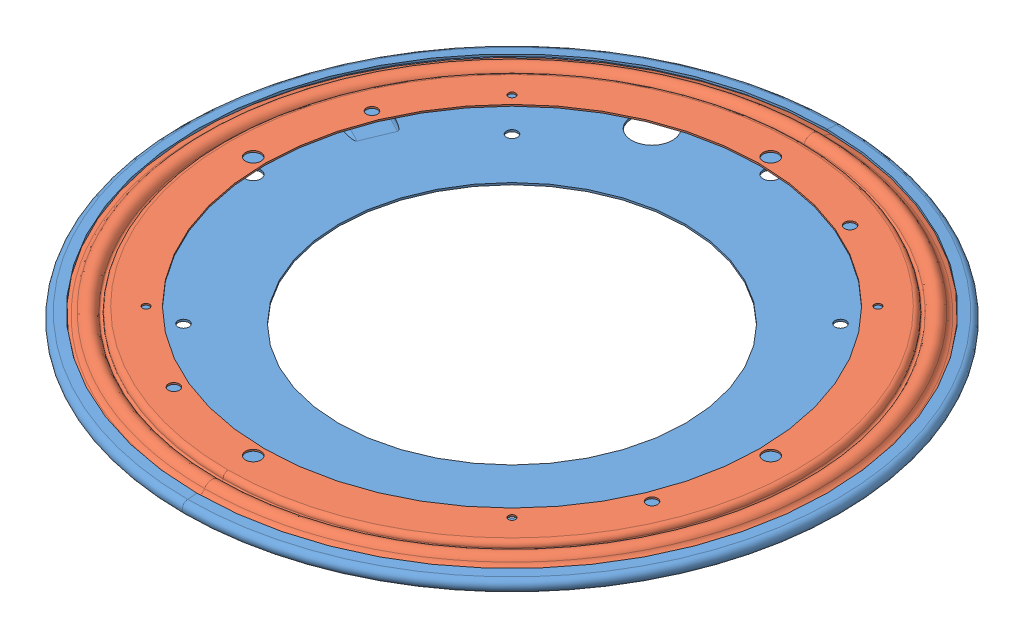
SolidWorks assembly GE-20150, configuration Default. Lengths in mm.
Overall size (306.54 10.35 306.54).
139 component instances, 3 part files, 0 mates.
Components (placement in the parent):
- triangle-mfg-lazy-susan-bearing-12c.STEP-1: triangle-mfg-lazy-susan-bearing-12c.STEP [Default] at origin size (306.54 10.35 306.54)
  - MSTR 12 Inch Locking Race_1865a.STEP-1: MSTR 12 Inch Locking Race_1865a.STEP [Default] at origin size (306.54 5.95 306.54)
  - MSTR 12 Inch Plain Race_1866.STEP-1: MSTR 12 Inch Plain Race_1866.STEP [Default] at (0 2.1844 0) x (-1 0 0) z (0 0 -1) size (297.66 5.77 297.66)
  - MSTR Suzie Ball_Balls12.STEP-1: MSTR Suzie Ball_Balls12.STEP [Default] at (139.5019 4.0386 0) x (-0.848035 -0.486854 -0.209308) z (-0.404097 0.338557 0.849756) size (6.35 6.35 6.35)
  - MSTR Suzie Ball_Balls12.STEP-2: MSTR Suzie Ball_Balls12.STEP [Default] at (139.353 4.0386 6.4427) x (-0.837464 -0.486854 -0.24825) z (-0.442911 0.338557 0.830186) size (6.35 6.35 6.35)
  - MSTR Suzie Ball_Balls12.STEP-3: MSTR Suzie Ball_Balls12.STEP [Default] at (138.9068 4.0386 12.8716) x (-0.825105 -0.486854 -0.286662) z (-0.480779 0.338557 0.808845) size (6.35 6.35 6.35)
  - MSTR Suzie Ball_Balls12.STEP-4: MSTR Suzie Ball_Balls12.STEP [Default] at (138.1641 4.0386 19.2731) x (-0.810985 -0.486854 -0.324463) z (-0.517621 0.338557 0.785778) size (6.35 6.35 6.35)
  - MSTR Suzie Ball_Balls12.STEP-5: MSTR Suzie Ball_Balls12.STEP [Default] at (137.1266 4.0386 25.6334) x (-0.795135 -0.486854 -0.361571) z (-0.553359 0.338557 0.761034) size (6.35 6.35 6.35)
  - MSTR Suzie Ball_Balls12.STEP-6: MSTR Suzie Ball_Balls12.STEP [Default] at (135.7964 4.0386 31.939) x (-0.777588 -0.486854 -0.397907) z (-0.587916 0.338557 0.734666) size (6.35 6.35 6.35)
  - MSTR Suzie Ball_Balls12.STEP-7: MSTR Suzie Ball_Balls12.STEP [Default] at (134.1765 4.0386 38.1765) x (-0.758382 -0.486854 -0.433394) z (-0.621218 0.338557 0.70673) size (6.35 6.35 6.35)
  - MSTR Suzie Ball_Balls12.STEP-8: MSTR Suzie Ball_Balls12.STEP [Default] at (132.2702 4.0386 44.3325) x (-0.737557 -0.486854 -0.467956) z (-0.653194 0.338557 0.677286) size (6.35 6.35 6.35)
  - MSTR Suzie Ball_Balls12.STEP-9: MSTR Suzie Ball_Balls12.STEP [Default] at (130.0816 4.0386 50.3939) x (-0.715158 -0.486854 -0.50152) z (-0.683777 0.338557 0.646397) size (6.35 6.35 6.35)
  - MSTR Suzie Ball_Balls12.STEP-10: MSTR Suzie Ball_Balls12.STEP [Default] at (127.6155 4.0386 56.3477) x (-0.691233 -0.486854 -0.534013) z (-0.7129 0.338557 0.614128) size (6.35 6.35 6.35)
  - MSTR Suzie Ball_Balls12.STEP-11: MSTR Suzie Ball_Balls12.STEP [Default] at (124.877 4.0386 62.1813) x (-0.665833 -0.486854 -0.565367) z (-0.740502 0.338557 0.580548) size (6.35 6.35 6.35)
  - MSTR Suzie Ball_Balls12.STEP-12: MSTR Suzie Ball_Balls12.STEP [Default] at (121.872 4.0386 67.8822) x (-0.639012 -0.486854 -0.595514) z (-0.766523 0.338557 0.54573) size (6.35 6.35 6.35)
  - MSTR Suzie Ball_Balls12.STEP-13: MSTR Suzie Ball_Balls12.STEP [Default] at (118.6069 4.0386 73.4383) x (-0.610827 -0.486854 -0.624391) z (-0.790909 0.338557 0.509747) size (6.35 6.35 6.35)
  - MSTR Suzie Ball_Balls12.STEP-14: MSTR Suzie Ball_Balls12.STEP [Default] at (115.0887 4.0386 78.8376) x (-0.581339 -0.486854 -0.651934) z (-0.813607 0.338557 0.472676) size (6.35 6.35 6.35)
  - MSTR Suzie Ball_Balls12.STEP-15: MSTR Suzie Ball_Balls12.STEP [Default] at (111.3249 4.0386 84.0687) x (-0.55061 -0.486854 -0.678087) z (-0.834569 0.338557 0.434597) size (6.35 6.35 6.35)
  - MSTR Suzie Ball_Balls12.STEP-16: MSTR Suzie Ball_Balls12.STEP [Default] at (107.3235 4.0386 89.1203) x (-0.518706 -0.486854 -0.702793) z (-0.853749 0.338557 0.39559) size (6.35 6.35 6.35)
  - MSTR Suzie Ball_Balls12.STEP-17: MSTR Suzie Ball_Balls12.STEP [Default] at (103.0931 4.0386 93.9818) x (-0.485695 -0.486854 -0.725998) z (-0.871108 0.338557 0.355738) size (6.35 6.35 6.35)
  - MSTR Suzie Ball_Balls12.STEP-18: MSTR Suzie Ball_Balls12.STEP [Default] at (98.6427 4.0386 98.6427) x (-0.451648 -0.486854 -0.747655) z (-0.886608 0.338557 0.315128) size (6.35 6.35 6.35)
  - MSTR Suzie Ball_Balls12.STEP-19: MSTR Suzie Ball_Balls12.STEP [Default] at (93.9818 4.0386 103.0931) x (-0.416637 -0.486854 -0.767716) z (-0.900216 0.338557 0.273845) size (6.35 6.35 6.35)
  - MSTR Suzie Ball_Balls12.STEP-20: MSTR Suzie Ball_Balls12.STEP [Default] at (89.1203 4.0386 107.3235) x (-0.380736 -0.486854 -0.786138) z (-0.911902 0.338557 0.231978) size (6.35 6.35 6.35)
  - MSTR Suzie Ball_Balls12.STEP-21: MSTR Suzie Ball_Balls12.STEP [Default] at (84.0687 4.0386 111.3249) x (-0.344024 -0.486854 -0.802883) z (-0.921643 0.338557 0.189616) size (6.35 6.35 6.35)
  - MSTR Suzie Ball_Balls12.STEP-22: MSTR Suzie Ball_Balls12.STEP [Default] at (78.8376 4.0386 115.0887) x (-0.306577 -0.486854 -0.817915) z (-0.929416 0.338557 0.146849) size (6.35 6.35 6.35)
  - MSTR Suzie Ball_Balls12.STEP-23: MSTR Suzie Ball_Balls12.STEP [Default] at (73.4383 4.0386 118.6069) x (-0.268475 -0.486854 -0.831201) z (-0.935207 0.338557 0.103768) size (6.35 6.35 6.35)
  - MSTR Suzie Ball_Balls12.STEP-24: MSTR Suzie Ball_Balls12.STEP [Default] at (67.8822 4.0386 121.872) x (-0.229801 -0.486854 -0.842713) z (-0.939001 0.338557 0.060466) size (6.35 6.35 6.35)
  - MSTR Suzie Ball_Balls12.STEP-25: MSTR Suzie Ball_Balls12.STEP [Default] at (62.1813 4.0386 124.877) x (-0.190637 -0.486854 -0.852427) z (-0.940792 0.338557 0.017036) size (6.35 6.35 6.35)
  - MSTR Suzie Ball_Balls12.STEP-26: MSTR Suzie Ball_Balls12.STEP [Default] at (56.3477 4.0386 127.6155) x (-0.151065 -0.486854 -0.860321) z (-0.940575 0.338557 -0.026432) size (6.35 6.35 6.35)
  - MSTR Suzie Ball_Balls12.STEP-27: MSTR Suzie Ball_Balls12.STEP [Default] at (50.3939 4.0386 130.0816) x (-0.111171 -0.486854 -0.86638) z (-0.93835 0.338557 -0.069842) size (6.35 6.35 6.35)
  - MSTR Suzie Ball_Balls12.STEP-28: MSTR Suzie Ball_Balls12.STEP [Default] at (44.3325 4.0386 132.2702) x (-0.07104 -0.486854 -0.87059) z (-0.934124 0.338557 -0.113104) size (6.35 6.35 6.35)
  - MSTR Suzie Ball_Balls12.STEP-29: MSTR Suzie Ball_Balls12.STEP [Default] at (38.1765 4.0386 134.1765) x (-0.030758 -0.486854 -0.872942) z (-0.927903 0.338557 -0.156124) size (6.35 6.35 6.35)
  - MSTR Suzie Ball_Balls12.STEP-30: MSTR Suzie Ball_Balls12.STEP [Default] at (31.939 4.0386 135.7964) x (0.009591 -0.486854 -0.873431) z (-0.919703 0.338557 -0.198812) size (6.35 6.35 6.35)
  - MSTR Suzie Ball_Balls12.STEP-31: MSTR Suzie Ball_Balls12.STEP [Default] at (25.6334 4.0386 137.1266) x (0.049918 -0.486854 -0.872056) z (-0.90954 0.338557 -0.241075) size (6.35 6.35 6.35)
  - MSTR Suzie Ball_Balls12.STEP-32: MSTR Suzie Ball_Balls12.STEP [Default] at (19.2731 4.0386 138.1641) x (0.09014 -0.486854 -0.86882) z (-0.897435 0.338557 -0.282823) size (6.35 6.35 6.35)
  - MSTR Suzie Ball_Balls12.STEP-33: MSTR Suzie Ball_Balls12.STEP [Default] at (12.8716 4.0386 138.9068) x (0.130169 -0.486854 -0.86373) z (-0.883416 0.338557 -0.323968) size (6.35 6.35 6.35)
  - MSTR Suzie Ball_Balls12.STEP-34: MSTR Suzie Ball_Balls12.STEP [Default] at (6.4427 4.0386 139.353) x (0.16992 -0.486854 -0.856797) z (-0.867512 0.338557 -0.364421) size (6.35 6.35 6.35)
  - MSTR Suzie Ball_Balls12.STEP-35: MSTR Suzie Ball_Balls12.STEP [Default] at (0 4.0386 139.5019) x (0.209308 -0.486854 -0.848035) z (-0.849756 0.338557 -0.404097) size (6.35 6.35 6.35)
  - MSTR Suzie Ball_Balls12.STEP-36: MSTR Suzie Ball_Balls12.STEP [Default] at (-6.4427 4.0386 139.353) x (0.24825 -0.486854 -0.837464) z (-0.830186 0.338557 -0.442911) size (6.35 6.35 6.35)
  - MSTR Suzie Ball_Balls12.STEP-37: MSTR Suzie Ball_Balls12.STEP [Default] at (-12.8716 4.0386 138.9068) x (0.286662 -0.486854 -0.825105) z (-0.808845 0.338557 -0.480779) size (6.35 6.35 6.35)
  - MSTR Suzie Ball_Balls12.STEP-38: MSTR Suzie Ball_Balls12.STEP [Default] at (-19.2731 4.0386 138.1641) x (0.324463 -0.486854 -0.810985) z (-0.785778 0.338557 -0.517621) size (6.35 6.35 6.35)
  - MSTR Suzie Ball_Balls12.STEP-39: MSTR Suzie Ball_Balls12.STEP [Default] at (-25.6334 4.0386 137.1266) x (0.361571 -0.486854 -0.795135) z (-0.761034 0.338557 -0.553359) size (6.35 6.35 6.35)
  - MSTR Suzie Ball_Balls12.STEP-40: MSTR Suzie Ball_Balls12.STEP [Default] at (-31.939 4.0386 135.7964) x (0.397907 -0.486854 -0.777588) z (-0.734666 0.338557 -0.587916) size (6.35 6.35 6.35)
  - MSTR Suzie Ball_Balls12.STEP-41: MSTR Suzie Ball_Balls12.STEP [Default] at (-38.1765 4.0386 134.1765) x (0.433394 -0.486854 -0.758382) z (-0.70673 0.338557 -0.621218) size (6.35 6.35 6.35)
  - MSTR Suzie Ball_Balls12.STEP-42: MSTR Suzie Ball_Balls12.STEP [Default] at (-44.3325 4.0386 132.2702) x (0.467956 -0.486854 -0.737557) z (-0.677286 0.338557 -0.653194) size (6.35 6.35 6.35)
  - MSTR Suzie Ball_Balls12.STEP-43: MSTR Suzie Ball_Balls12.STEP [Default] at (-50.3939 4.0386 130.0816) x (0.50152 -0.486854 -0.715158) z (-0.646397 0.338557 -0.683777) size (6.35 6.35 6.35)
  - MSTR Suzie Ball_Balls12.STEP-44: MSTR Suzie Ball_Balls12.STEP [Default] at (-56.3477 4.0386 127.6155) x (0.534013 -0.486854 -0.691233) z (-0.614128 0.338557 -0.7129) size (6.35 6.35 6.35)
  - MSTR Suzie Ball_Balls12.STEP-45: MSTR Suzie Ball_Balls12.STEP [Default] at (-62.1813 4.0386 124.877) x (0.565367 -0.486854 -0.665833) z (-0.580548 0.338557 -0.740502) size (6.35 6.35 6.35)
  - MSTR Suzie Ball_Balls12.STEP-46: MSTR Suzie Ball_Balls12.STEP [Default] at (-67.8822 4.0386 121.872) x (0.595514 -0.486854 -0.639012) z (-0.54573 0.338557 -0.766523) size (6.35 6.35 6.35)
  - MSTR Suzie Ball_Balls12.STEP-47: MSTR Suzie Ball_Balls12.STEP [Default] at (-73.4383 4.0386 118.6069) x (0.624391 -0.486854 -0.610827) z (-0.509747 0.338557 -0.790909) size (6.35 6.35 6.35)
  - MSTR Suzie Ball_Balls12.STEP-48: MSTR Suzie Ball_Balls12.STEP [Default] at (-78.8376 4.0386 115.0887) x (0.651934 -0.486854 -0.581339) z (-0.472676 0.338557 -0.813607) size (6.35 6.35 6.35)
  - MSTR Suzie Ball_Balls12.STEP-49: MSTR Suzie Ball_Balls12.STEP [Default] at (-84.0687 4.0386 111.3249) x (0.678087 -0.486854 -0.55061) z (-0.434597 0.338557 -0.834569) size (6.35 6.35 6.35)
  - MSTR Suzie Ball_Balls12.STEP-50: MSTR Suzie Ball_Balls12.STEP [Default] at (-89.1203 4.0386 107.3235) x (0.702793 -0.486854 -0.518706) z (-0.39559 0.338557 -0.853749) size (6.35 6.35 6.35)
  - MSTR Suzie Ball_Balls12.STEP-51: MSTR Suzie Ball_Balls12.STEP [Default] at (-93.9818 4.0386 103.0931) x (0.725998 -0.486854 -0.485695) z (-0.355738 0.338557 -0.871108) size (6.35 6.35 6.35)
  - MSTR Suzie Ball_Balls12.STEP-52: MSTR Suzie Ball_Balls12.STEP [Default] at (-98.6427 4.0386 98.6427) x (0.747655 -0.486854 -0.451648) z (-0.315128 0.338557 -0.886608) size (6.35 6.35 6.35)
  - MSTR Suzie Ball_Balls12.STEP-53: MSTR Suzie Ball_Balls12.STEP [Default] at (-103.0931 4.0386 93.9818) x (0.767716 -0.486854 -0.416637) z (-0.273845 0.338557 -0.900216) size (6.35 6.35 6.35)
  - MSTR Suzie Ball_Balls12.STEP-54: MSTR Suzie Ball_Balls12.STEP [Default] at (-107.3235 4.0386 89.1203) x (0.786138 -0.486854 -0.380736) z (-0.231978 0.338557 -0.911902) size (6.35 6.35 6.35)
  - MSTR Suzie Ball_Balls12.STEP-55: MSTR Suzie Ball_Balls12.STEP [Default] at (-111.3249 4.0386 84.0687) x (0.802883 -0.486854 -0.344024) z (-0.189616 0.338557 -0.921643) size (6.35 6.35 6.35)
  - MSTR Suzie Ball_Balls12.STEP-56: MSTR Suzie Ball_Balls12.STEP [Default] at (-115.0887 4.0386 78.8376) x (0.817915 -0.486854 -0.306577) z (-0.146849 0.338557 -0.929416) size (6.35 6.35 6.35)
  - MSTR Suzie Ball_Balls12.STEP-57: MSTR Suzie Ball_Balls12.STEP [Default] at (-118.6069 4.0386 73.4383) x (0.831201 -0.486854 -0.268475) z (-0.103768 0.338557 -0.935207) size (6.35 6.35 6.35)
  - MSTR Suzie Ball_Balls12.STEP-58: MSTR Suzie Ball_Balls12.STEP [Default] at (-121.872 4.0386 67.8822) x (0.842713 -0.486854 -0.229801) z (-0.060466 0.338557 -0.939001) size (6.35 6.35 6.35)
  - MSTR Suzie Ball_Balls12.STEP-59: MSTR Suzie Ball_Balls12.STEP [Default] at (-124.877 4.0386 62.1813) x (0.852427 -0.486854 -0.190637) z (-0.017036 0.338557 -0.940792) size (6.35 6.35 6.35)
  - MSTR Suzie Ball_Balls12.STEP-60: MSTR Suzie Ball_Balls12.STEP [Default] at (-127.6155 4.0386 56.3477) x (0.860321 -0.486854 -0.151065) z (0.026432 0.338557 -0.940575) size (6.35 6.35 6.35)
  - MSTR Suzie Ball_Balls12.STEP-61: MSTR Suzie Ball_Balls12.STEP [Default] at (-130.0816 4.0386 50.3939) x (0.86638 -0.486854 -0.111171) z (0.069842 0.338557 -0.93835) size (6.35 6.35 6.35)
  - MSTR Suzie Ball_Balls12.STEP-62: MSTR Suzie Ball_Balls12.STEP [Default] at (-132.2702 4.0386 44.3325) x (0.87059 -0.486854 -0.07104) z (0.113104 0.338557 -0.934124) size (6.35 6.35 6.35)
  - MSTR Suzie Ball_Balls12.STEP-63: MSTR Suzie Ball_Balls12.STEP [Default] at (-134.1765 4.0386 38.1765) x (0.872942 -0.486854 -0.030758) z (0.156124 0.338557 -0.927903) size (6.35 6.35 6.35)
  - MSTR Suzie Ball_Balls12.STEP-64: MSTR Suzie Ball_Balls12.STEP [Default] at (-135.7964 4.0386 31.939) x (0.873431 -0.486854 0.009591) z (0.198812 0.338557 -0.919703) size (6.35 6.35 6.35)
  - MSTR Suzie Ball_Balls12.STEP-65: MSTR Suzie Ball_Balls12.STEP [Default] at (-137.1266 4.0386 25.6334) x (0.872056 -0.486854 0.049918) z (0.241075 0.338557 -0.90954) size (6.35 6.35 6.35)
  - MSTR Suzie Ball_Balls12.STEP-66: MSTR Suzie Ball_Balls12.STEP [Default] at (-138.1641 4.0386 19.2731) x (0.86882 -0.486854 0.09014) z (0.282823 0.338557 -0.897435) size (6.35 6.35 6.35)
  - MSTR Suzie Ball_Balls12.STEP-67: MSTR Suzie Ball_Balls12.STEP [Default] at (-138.9068 4.0386 12.8716) x (0.86373 -0.486854 0.130169) z (0.323968 0.338557 -0.883416) size (6.35 6.35 6.35)
  - MSTR Suzie Ball_Balls12.STEP-68: MSTR Suzie Ball_Balls12.STEP [Default] at (-139.353 4.0386 6.4427) x (0.856797 -0.486854 0.16992) z (0.364421 0.338557 -0.867512) size (6.35 6.35 6.35)
  - MSTR Suzie Ball_Balls12.STEP-69: MSTR Suzie Ball_Balls12.STEP [Default] at (-139.5019 4.0386 0) x (0.848035 -0.486854 0.209308) z (0.404097 0.338557 -0.849756) size (6.35 6.35 6.35)
  - MSTR Suzie Ball_Balls12.STEP-70: MSTR Suzie Ball_Balls12.STEP [Default] at (-139.353 4.0386 -6.4427) x (0.837464 -0.486854 0.24825) z (0.442911 0.338557 -0.830186) size (6.35 6.35 6.35)
  - MSTR Suzie Ball_Balls12.STEP-71: MSTR Suzie Ball_Balls12.STEP [Default] at (-138.9068 4.0386 -12.8716) x (0.825105 -0.486854 0.286662) z (0.480779 0.338557 -0.808845) size (6.35 6.35 6.35)
  - MSTR Suzie Ball_Balls12.STEP-72: MSTR Suzie Ball_Balls12.STEP [Default] at (-138.1641 4.0386 -19.2731) x (0.810985 -0.486854 0.324463) z (0.517621 0.338557 -0.785778) size (6.35 6.35 6.35)
  - MSTR Suzie Ball_Balls12.STEP-73: MSTR Suzie Ball_Balls12.STEP [Default] at (-137.1266 4.0386 -25.6334) x (0.795135 -0.486854 0.361571) z (0.553359 0.338557 -0.761034) size (6.35 6.35 6.35)
  - MSTR Suzie Ball_Balls12.STEP-74: MSTR Suzie Ball_Balls12.STEP [Default] at (-135.7964 4.0386 -31.939) x (0.777588 -0.486854 0.397907) z (0.587916 0.338557 -0.734666) size (6.35 6.35 6.35)
  - MSTR Suzie Ball_Balls12.STEP-75: MSTR Suzie Ball_Balls12.STEP [Default] at (-134.1765 4.0386 -38.1765) x (0.758382 -0.486854 0.433394) z (0.621218 0.338557 -0.70673) size (6.35 6.35 6.35)
  - MSTR Suzie Ball_Balls12.STEP-76: MSTR Suzie Ball_Balls12.STEP [Default] at (-132.2702 4.0386 -44.3325) x (0.737557 -0.486854 0.467956) z (0.653194 0.338557 -0.677286) size (6.35 6.35 6.35)
  - MSTR Suzie Ball_Balls12.STEP-77: MSTR Suzie Ball_Balls12.STEP [Default] at (-130.0816 4.0386 -50.3939) x (0.715158 -0.486854 0.50152) z (0.683777 0.338557 -0.646397) size (6.35 6.35 6.35)
  - MSTR Suzie Ball_Balls12.STEP-78: MSTR Suzie Ball_Balls12.STEP [Default] at (-127.6155 4.0386 -56.3477) x (0.691233 -0.486854 0.534013) z (0.7129 0.338557 -0.614128) size (6.35 6.35 6.35)
  - MSTR Suzie Ball_Balls12.STEP-79: MSTR Suzie Ball_Balls12.STEP [Default] at (-124.877 4.0386 -62.1813) x (0.665833 -0.486854 0.565367) z (0.740502 0.338557 -0.580548) size (6.35 6.35 6.35)
  - MSTR Suzie Ball_Balls12.STEP-80: MSTR Suzie Ball_Balls12.STEP [Default] at (-121.872 4.0386 -67.8822) x (0.639012 -0.486854 0.595514) z (0.766523 0.338557 -0.54573) size (6.35 6.35 6.35)
  - MSTR Suzie Ball_Balls12.STEP-81: MSTR Suzie Ball_Balls12.STEP [Default] at (-118.6069 4.0386 -73.4383) x (0.610827 -0.486854 0.624391) z (0.790909 0.338557 -0.509747) size (6.35 6.35 6.35)
  - MSTR Suzie Ball_Balls12.STEP-82: MSTR Suzie Ball_Balls12.STEP [Default] at (-115.0887 4.0386 -78.8376) x (0.581339 -0.486854 0.651934) z (0.813607 0.338557 -0.472676) size (6.35 6.35 6.35)
  - MSTR Suzie Ball_Balls12.STEP-83: MSTR Suzie Ball_Balls12.STEP [Default] at (-111.3249 4.0386 -84.0687) x (0.55061 -0.486854 0.678087) z (0.834569 0.338557 -0.434597) size (6.35 6.35 6.35)
  - MSTR Suzie Ball_Balls12.STEP-84: MSTR Suzie Ball_Balls12.STEP [Default] at (-107.3235 4.0386 -89.1203) x (0.518706 -0.486854 0.702793) z (0.853749 0.338557 -0.39559) size (6.35 6.35 6.35)
  - MSTR Suzie Ball_Balls12.STEP-85: MSTR Suzie Ball_Balls12.STEP [Default] at (-103.0931 4.0386 -93.9818) x (0.485695 -0.486854 0.725998) z (0.871108 0.338557 -0.355738) size (6.35 6.35 6.35)
  - MSTR Suzie Ball_Balls12.STEP-86: MSTR Suzie Ball_Balls12.STEP [Default] at (-98.6427 4.0386 -98.6427) x (0.451648 -0.486854 0.747655) z (0.886608 0.338557 -0.315128) size (6.35 6.35 6.35)
  - MSTR Suzie Ball_Balls12.STEP-87: MSTR Suzie Ball_Balls12.STEP [Default] at (-93.9818 4.0386 -103.0931) x (0.416637 -0.486854 0.767716) z (0.900216 0.338557 -0.273845) size (6.35 6.35 6.35)
  - MSTR Suzie Ball_Balls12.STEP-88: MSTR Suzie Ball_Balls12.STEP [Default] at (-89.1203 4.0386 -107.3235) x (0.380736 -0.486854 0.786138) z (0.911902 0.338557 -0.231978) size (6.35 6.35 6.35)
  - MSTR Suzie Ball_Balls12.STEP-89: MSTR Suzie Ball_Balls12.STEP [Default] at (-84.0687 4.0386 -111.3249) x (0.344024 -0.486854 0.802883) z (0.921643 0.338557 -0.189616) size (6.35 6.35 6.35)
  - MSTR Suzie Ball_Balls12.STEP-90: MSTR Suzie Ball_Balls12.STEP [Default] at (-78.8376 4.0386 -115.0887) x (0.306577 -0.486854 0.817915) z (0.929416 0.338557 -0.146849) size (6.35 6.35 6.35)
  - MSTR Suzie Ball_Balls12.STEP-91: MSTR Suzie Ball_Balls12.STEP [Default] at (-73.4383 4.0386 -118.6069) x (0.268475 -0.486854 0.831201) z (0.935207 0.338557 -0.103768) size (6.35 6.35 6.35)
  - MSTR Suzie Ball_Balls12.STEP-92: MSTR Suzie Ball_Balls12.STEP [Default] at (-67.8822 4.0386 -121.872) x (0.229801 -0.486854 0.842713) z (0.939001 0.338557 -0.060466) size (6.35 6.35 6.35)
  - MSTR Suzie Ball_Balls12.STEP-93: MSTR Suzie Ball_Balls12.STEP [Default] at (-62.1813 4.0386 -124.877) x (0.190637 -0.486854 0.852427) z (0.940792 0.338557 -0.017036) size (6.35 6.35 6.35)
  - MSTR Suzie Ball_Balls12.STEP-94: MSTR Suzie Ball_Balls12.STEP [Default] at (-56.3477 4.0386 -127.6155) x (0.151065 -0.486854 0.860321) z (0.940575 0.338557 0.026432) size (6.35 6.35 6.35)
  - MSTR Suzie Ball_Balls12.STEP-95: MSTR Suzie Ball_Balls12.STEP [Default] at (-50.3939 4.0386 -130.0816) x (0.111171 -0.486854 0.86638) z (0.93835 0.338557 0.069842) size (6.35 6.35 6.35)
  - MSTR Suzie Ball_Balls12.STEP-96: MSTR Suzie Ball_Balls12.STEP [Default] at (-44.3325 4.0386 -132.2702) x (0.07104 -0.486854 0.87059) z (0.934124 0.338557 0.113104) size (6.35 6.35 6.35)
  - MSTR Suzie Ball_Balls12.STEP-97: MSTR Suzie Ball_Balls12.STEP [Default] at (-38.1765 4.0386 -134.1765) x (0.030758 -0.486854 0.872942) z (0.927903 0.338557 0.156124) size (6.35 6.35 6.35)
  - MSTR Suzie Ball_Balls12.STEP-98: MSTR Suzie Ball_Balls12.STEP [Default] at (-31.939 4.0386 -135.7964) x (-0.009591 -0.486854 0.873431) z (0.919703 0.338557 0.198812) size (6.35 6.35 6.35)
  - MSTR Suzie Ball_Balls12.STEP-99: MSTR Suzie Ball_Balls12.STEP [Default] at (-25.6334 4.0386 -137.1266) x (-0.049918 -0.486854 0.872056) z (0.90954 0.338557 0.241075) size (6.35 6.35 6.35)
  - MSTR Suzie Ball_Balls12.STEP-100: MSTR Suzie Ball_Balls12.STEP [Default] at (-19.2731 4.0386 -138.1641) x (-0.09014 -0.486854 0.86882) z (0.897435 0.338557 0.282823) size (6.35 6.35 6.35)
  - MSTR Suzie Ball_Balls12.STEP-101: MSTR Suzie Ball_Balls12.STEP [Default] at (-12.8716 4.0386 -138.9068) x (-0.130169 -0.486854 0.86373) z (0.883416 0.338557 0.323968) size (6.35 6.35 6.35)
  - MSTR Suzie Ball_Balls12.STEP-102: MSTR Suzie Ball_Balls12.STEP [Default] at (-6.4427 4.0386 -139.353) x (-0.16992 -0.486854 0.856797) z (0.867512 0.338557 0.364421) size (6.35 6.35 6.35)
  - MSTR Suzie Ball_Balls12.STEP-103: MSTR Suzie Ball_Balls12.STEP [Default] at (0 4.0386 -139.5019) x (-0.209308 -0.486854 0.848035) z (0.849756 0.338557 0.404097) size (6.35 6.35 6.35)
  - MSTR Suzie Ball_Balls12.STEP-104: MSTR Suzie Ball_Balls12.STEP [Default] at (6.4427 4.0386 -139.353) x (-0.24825 -0.486854 0.837464) z (0.830186 0.338557 0.442911) size (6.35 6.35 6.35)
  - MSTR Suzie Ball_Balls12.STEP-105: MSTR Suzie Ball_Balls12.STEP [Default] at (12.8716 4.0386 -138.9068) x (-0.286662 -0.486854 0.825105) z (0.808845 0.338557 0.480779) size (6.35 6.35 6.35)
  - MSTR Suzie Ball_Balls12.STEP-106: MSTR Suzie Ball_Balls12.STEP [Default] at (19.2731 4.0386 -138.1641) x (-0.324463 -0.486854 0.810985) z (0.785778 0.338557 0.517621) size (6.35 6.35 6.35)
  - MSTR Suzie Ball_Balls12.STEP-107: MSTR Suzie Ball_Balls12.STEP [Default] at (25.6334 4.0386 -137.1266) x (-0.361571 -0.486854 0.795135) z (0.761034 0.338557 0.553359) size (6.35 6.35 6.35)
  - MSTR Suzie Ball_Balls12.STEP-108: MSTR Suzie Ball_Balls12.STEP [Default] at (31.939 4.0386 -135.7964) x (-0.397907 -0.486854 0.777588) z (0.734666 0.338557 0.587916) size (6.35 6.35 6.35)
  - MSTR Suzie Ball_Balls12.STEP-109: MSTR Suzie Ball_Balls12.STEP [Default] at (38.1765 4.0386 -134.1765) x (-0.433394 -0.486854 0.758382) z (0.70673 0.338557 0.621218) size (6.35 6.35 6.35)
  - MSTR Suzie Ball_Balls12.STEP-110: MSTR Suzie Ball_Balls12.STEP [Default] at (44.3325 4.0386 -132.2702) x (-0.467956 -0.486854 0.737557) z (0.677286 0.338557 0.653194) size (6.35 6.35 6.35)
  - MSTR Suzie Ball_Balls12.STEP-111: MSTR Suzie Ball_Balls12.STEP [Default] at (50.3939 4.0386 -130.0816) x (-0.50152 -0.486854 0.715158) z (0.646397 0.338557 0.683777) size (6.35 6.35 6.35)
  - MSTR Suzie Ball_Balls12.STEP-112: MSTR Suzie Ball_Balls12.STEP [Default] at (56.3477 4.0386 -127.6155) x (-0.534013 -0.486854 0.691233) z (0.614128 0.338557 0.7129) size (6.35 6.35 6.35)
  - MSTR Suzie Ball_Balls12.STEP-113: MSTR Suzie Ball_Balls12.STEP [Default] at (62.1813 4.0386 -124.877) x (-0.565367 -0.486854 0.665833) z (0.580548 0.338557 0.740502) size (6.35 6.35 6.35)
  - MSTR Suzie Ball_Balls12.STEP-114: MSTR Suzie Ball_Balls12.STEP [Default] at (67.8822 4.0386 -121.872) x (-0.595514 -0.486854 0.639012) z (0.54573 0.338557 0.766523) size (6.35 6.35 6.35)
  - MSTR Suzie Ball_Balls12.STEP-115: MSTR Suzie Ball_Balls12.STEP [Default] at (73.4383 4.0386 -118.6069) x (-0.624391 -0.486854 0.610827) z (0.509747 0.338557 0.790909) size (6.35 6.35 6.35)
  - MSTR Suzie Ball_Balls12.STEP-116: MSTR Suzie Ball_Balls12.STEP [Default] at (78.8376 4.0386 -115.0887) x (-0.651934 -0.486854 0.581339) z (0.472676 0.338557 0.813607) size (6.35 6.35 6.35)
  - MSTR Suzie Ball_Balls12.STEP-117: MSTR Suzie Ball_Balls12.STEP [Default] at (84.0687 4.0386 -111.3249) x (-0.678087 -0.486854 0.55061) z (0.434597 0.338557 0.834569) size (6.35 6.35 6.35)
  - MSTR Suzie Ball_Balls12.STEP-118: MSTR Suzie Ball_Balls12.STEP [Default] at (89.1203 4.0386 -107.3235) x (-0.702793 -0.486854 0.518706) z (0.39559 0.338557 0.853749) size (6.35 6.35 6.35)
  - MSTR Suzie Ball_Balls12.STEP-119: MSTR Suzie Ball_Balls12.STEP [Default] at (93.9818 4.0386 -103.0931) x (-0.725998 -0.486854 0.485695) z (0.355738 0.338557 0.871108) size (6.35 6.35 6.35)
  - MSTR Suzie Ball_Balls12.STEP-120: MSTR Suzie Ball_Balls12.STEP [Default] at (98.6427 4.0386 -98.6427) x (-0.747655 -0.486854 0.451648) z (0.315128 0.338557 0.886608) size (6.35 6.35 6.35)
  - MSTR Suzie Ball_Balls12.STEP-121: MSTR Suzie Ball_Balls12.STEP [Default] at (103.0931 4.0386 -93.9818) x (-0.767716 -0.486854 0.416637) z (0.273845 0.338557 0.900216) size (6.35 6.35 6.35)
  - MSTR Suzie Ball_Balls12.STEP-122: MSTR Suzie Ball_Balls12.STEP [Default] at (107.3235 4.0386 -89.1203) x (-0.786138 -0.486854 0.380736) z (0.231978 0.338557 0.911902) size (6.35 6.35 6.35)
  - MSTR Suzie Ball_Balls12.STEP-123: MSTR Suzie Ball_Balls12.STEP [Default] at (111.3249 4.0386 -84.0687) x (-0.802883 -0.486854 0.344024) z (0.189616 0.338557 0.921643) size (6.35 6.35 6.35)
  - MSTR Suzie Ball_Balls12.STEP-124: MSTR Suzie Ball_Balls12.STEP [Default] at (115.0887 4.0386 -78.8376) x (-0.817915 -0.486854 0.306577) z (0.146849 0.338557 0.929416) size (6.35 6.35 6.35)
  - MSTR Suzie Ball_Balls12.STEP-125: MSTR Suzie Ball_Balls12.STEP [Default] at (118.6069 4.0386 -73.4383) x (-0.831201 -0.486854 0.268475) z (0.103768 0.338557 0.935207) size (6.35 6.35 6.35)
  - MSTR Suzie Ball_Balls12.STEP-126: MSTR Suzie Ball_Balls12.STEP [Default] at (121.872 4.0386 -67.8822) x (-0.842713 -0.486854 0.229801) z (0.060466 0.338557 0.939001) size (6.35 6.35 6.35)
  - MSTR Suzie Ball_Balls12.STEP-127: MSTR Suzie Ball_Balls12.STEP [Default] at (124.877 4.0386 -62.1813) x (-0.852427 -0.486854 0.190637) z (0.017036 0.338557 0.940792) size (6.35 6.35 6.35)
  - MSTR Suzie Ball_Balls12.STEP-128: MSTR Suzie Ball_Balls12.STEP [Default] at (127.6155 4.0386 -56.3477) x (-0.860321 -0.486854 0.151065) z (-0.026432 0.338557 0.940575) size (6.35 6.35 6.35)
  - MSTR Suzie Ball_Balls12.STEP-129: MSTR Suzie Ball_Balls12.STEP [Default] at (130.0816 4.0386 -50.3939) x (-0.86638 -0.486854 0.111171) z (-0.069842 0.338557 0.93835) size (6.35 6.35 6.35)
  - MSTR Suzie Ball_Balls12.STEP-130: MSTR Suzie Ball_Balls12.STEP [Default] at (132.2702 4.0386 -44.3325) x (-0.87059 -0.486854 0.07104) z (-0.113104 0.338557 0.934124) size (6.35 6.35 6.35)
  - MSTR Suzie Ball_Balls12.STEP-131: MSTR Suzie Ball_Balls12.STEP [Default] at (134.1765 4.0386 -38.1765) x (-0.872942 -0.486854 0.030758) z (-0.156124 0.338557 0.927903) size (6.35 6.35 6.35)
  - MSTR Suzie Ball_Balls12.STEP-132: MSTR Suzie Ball_Balls12.STEP [Default] at (135.7964 4.0386 -31.939) x (-0.873431 -0.486854 -0.009591) z (-0.198812 0.338557 0.919703) size (6.35 6.35 6.35)
  - MSTR Suzie Ball_Balls12.STEP-133: MSTR Suzie Ball_Balls12.STEP [Default] at (137.1266 4.0386 -25.6334) x (-0.872056 -0.486854 -0.049918) z (-0.241075 0.338557 0.90954) size (6.35 6.35 6.35)
  - MSTR Suzie Ball_Balls12.STEP-134: MSTR Suzie Ball_Balls12.STEP [Default] at (138.1641 4.0386 -19.2731) x (-0.86882 -0.486854 -0.09014) z (-0.282823 0.338557 0.897435) size (6.35 6.35 6.35)
  - MSTR Suzie Ball_Balls12.STEP-135: MSTR Suzie Ball_Balls12.STEP [Default] at (138.9068 4.0386 -12.8716) x (-0.86373 -0.486854 -0.130169) z (-0.323968 0.338557 0.883416) size (6.35 6.35 6.35)
  - MSTR Suzie Ball_Balls12.STEP-136: MSTR Suzie Ball_Balls12.STEP [Default] at (139.353 4.0386 -6.4427) x (-0.856797 -0.486854 -0.16992) z (-0.364421 0.338557 0.867512) size (6.35 6.35 6.35)
